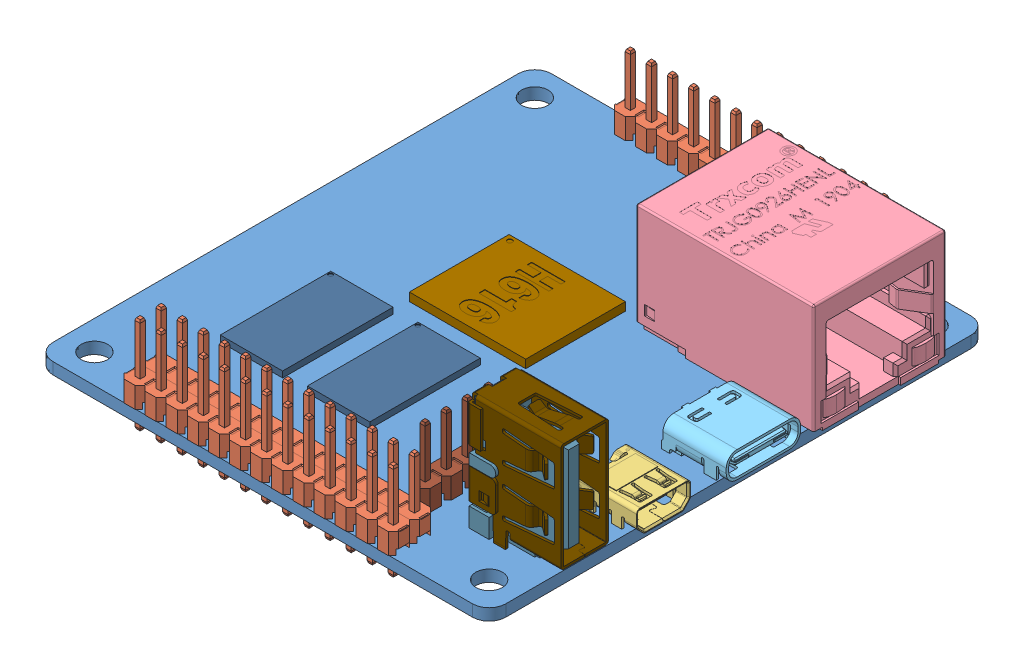
SolidWorks assembly OPiZero2, configuration Default. Lengths in mm.
Overall size (67.58 17.95 60.04).
23 component instances, 18 part files, 26 mates.
Components (placement in the parent):
- pcb_pi-1: pcb_pi [Not Open] [Default] at origin size (67.58 1.4 60)
- PLS-13.step-1: PLS-13.step [Not Open] [Default] at (-15.98 1.4 26.232) x (1 0 0) z (0 1 0) size (33.02 2.54 11.6)
- PLS-13.step-2: PLS-13.step [Not Open] [Default] at (-15.98 1.4 28.772) x (1 0 0) z (0 1 0) size (33.02 2.54 11.6)
- PLS-13.step-3: PLS-13.step [Not Open] [Default] at (-14.48 1.4 -28.73) x (1 0 0) z (0 1 0) size (33.02 2.54 11.6)
- 11.0 Female micro HDMI connector-2: 11.0 Female micro HDMI connector [Not Open] [Domyślna] at (20.75 2.85 10.0003) x (0 0 -1) z (1 0 0) size (6.5 3.51 7.5)
- 12.0 Gigabit ethernet port raspberry-2: 12.0 Gigabit ethernet port raspberry [Not Open] [Default] at (28.25 8.325 -16) x (0 0 -1) z (1 0 0) size (16.1 17.2 21.46)
- 10.0 Female USB connector-3: 10.0 Female USB connector [Not Open] [Domyślna] at (20.64 2.98 -2) x (0 0 -1) z (1 0 0) size (8.94 3.96 8.33)
- Card slot assembly-1: Card slot assembly [Domyślna] at (-30.8948 -12.71 -19.3913) x (0 0 -1) z (0 1 0) size (23.54 11.4 1.48)
  - card slot part 2 metal pin-1: card slot part 2 metal pin [Not Open] [Domyślna] at (-3.5293 -7.6678 12.2938) x (0 -1 0) z (1 0 0) size (7.95 0.89 8.04)
  - sd card slot v1-1: sd card slot v1 [Not Open] [Domyślna] at (-18.1743 -9.7848 12.71) x (-1 0 0) z (0 0 -1) size (23.42 10.28 1.3)
  - part 3 v1-1: part 3 v1 [Not Open] [Domyślna] at (-6.4643 -9.3448 11.38) x (1 0 0) z (0 0 -1) size (11.95 11.4 1.45)
- H616-1: H616 [Not Open] [Default] at (-2.9276 1.52 -3.5752) x (0 0 1) z (-1 0 0) size (12 1.12 14)
- DDR3-1: DDR3 [Not Open] [Default] at (-13.1619 1.7 11.5463) size (7.5 1.03 13.3)
- DDR3-2: DDR3 [Not Open] [Default] at (-2.6086 1.7 11.6068) size (7.5 1.03 13.3)
- PLS-4-1: PLS-4 [Not Open] [Default] at (11.9038 1.4 14.7353) x (0 0 1) z (0 1 0) size (10.16 2.54 11.6)
- RTL-1: RTL [Not Open] [Default] at (2.2806 1.825 -19.9189) size (5 0.85 5)
- 614004184726-1: 614004184726 [Default] at (18.425 9 19.5) x (0 0 -1) z (0 1 0) size (7.12 11 17.04)
  - 614004184726_01-1: 614004184726_01 [Default] at origin size (3.86 8.85 14.75)
  - 614004184726_02-1: 614004184726_02 [Default] at origin size (6.42 10.25 13.85)
  - 614004184726_03-1: 614004184726_03 [Default] at origin size (2.9 8.85 11.95)
  - 614004184726_04-1: 614004184726_04 [Default] at origin size (2.25 8.85 9.95)
  - 614004184726_05-1: 614004184726_05 [Default] at origin size (2.99 8.85 7.45)
  - 614004184726_06-1: 614004184726_06 [Default] at origin size (7.12 11 17.04)
Mates (geometry in assembly coordinates):
- Coincident6: coincident anti-aligned: plane of pcb-1 through (0 1.4 0) normal (0 1 0); plane of PLS-13.step-1 through (-13.44 1.4 26.232) normal (0 -1 0)
- Lock1: lock: unknown of PLS-13.step-1; unknown of PLS-13.step-2
- Parallel5: parallel anti-aligned: line of pcb-1 through (-17.25 1.4 30) axis (0 0 -1); line of PLS-13.step-2 through (-17.25 2.1 28.102) axis (0 0 1)
- Coincident15: coincident: line of pcb-1 through (-17.25 1.4 30) axis (0 0 -1); plane of PLS-13.step-2 through (-17.25 1.4 28.102) normal (-1 0 0)
- Coincident16: coincident anti-aligned: plane of pcb-1 through (0 1.4 0) normal (0 1 0); plane of PLS-13.step-3 through (-11.94 1.4 -28.73) normal (0 -1 0)
- Coincident18: coincident: line of pcb-1 through (-15.75 1.4 -30) axis (0 0 1); plane of PLS-13.step-3 through (-15.75 1.4 -29.4) normal (-1 0 0)
- Coincident19: coincident: line of pcb-1 through (-15.75 1.4 -30) axis (1 0 0); plane of PLS-13.step-3 through (-3.65 1.4 -30) normal (0 0 -1)
- Coincident27: coincident anti-aligned: plane of pcb-1 through (0 1.4 0) normal (0 1 0); plane of 11.0 Female micro HDMI connector-2 through (22.75 1.4 8.1324) normal (0 -1 0)
- Coincident28: coincident: line of pcb-1 through (28.25 1.4 -30) axis (0 0 1); plane of 11.0 Female micro HDMI connector-2 through (28.25 1.85 12.1558) normal (1 0 0)
- Coincident29: coincident anti-aligned: plane of pcb-1 through (0 1.4 0) normal (0 1 0); plane of 12.0 Gigabit ethernet port raspberry-2 through (28.25 1.4 -16) normal (0 -1 0)
- Coincident30: coincident: line of pcb-1 through (28.25 1.4 -30) axis (0 0 1); plane of 12.0 Gigabit ethernet port raspberry-2 through (28.25 8.325 -16) normal (1 0 0)
- Distance6: distance = 0.05 mm: plane of 12.0 Gigabit ethernet port raspberry-2 through (6.9 1.75 -23.95) normal (0 0 -1); line of pcb-1 through (28.25 1.4 -24) axis (-1 0 0)
- Coincident33: coincident anti-aligned: plane of pcb-1 through (0 1.4 0) normal (0 1 0); plane of 10.0 Female USB connector-3 through (28.25 1.4 1.17) normal (0 -1 0)
- Coincident34: coincident: line of pcb-1 through (28.25 1.4 -30) axis (0 0 1); plane of 10.0 Female USB connector-3 through (28.25 3.26 1.17) normal (1 0 0)
- Distance7: distance = 0.47 mm: plane of 10.0 Female USB connector-3 through (28.25 2.7 -6.47) normal (0 0 -1); line of pcb-1 through (28.25 1.4 -6) axis (-1 0 0)
- Coincident40: coincident anti-aligned: plane of pcb-1 through (0 0 0) normal (0 -1 0); plane of Card slot assembly-1/sd card slot v1-1 through (-25.75 0 -7.707) normal (0 1 0)
- Coincident41: coincident aligned: plane of pcb-1 through (-27.25 1.4 30) normal (-1 0 0); plane of Card slot assembly-1/part 3 v1-1 through (-27.25 -1.45 -18.902) normal (-1 0 0)
- Coincident43: coincident anti-aligned: plane of pcb-1 through (0 1.4 0) normal (0 1 0); plane of H616-1 through (-9.4026 1.4 -9.1252) normal (0 -1 0)
- Perpendicular1: perpendicular: plane of pcb-1 through (-27.25 1.4 30) normal (-1 0 0); plane of H616-1 through (-9.9276 2.52 -9.5752) normal (0 0 -1)
- Coincident45: coincident anti-aligned: plane of pcb-1 through (0 1.4 0) normal (0 1 0); circle of DDR3-1
- Coincident46: coincident anti-aligned: plane of pcb-1 through (0 1.4 0) normal (0 1 0); plane of DDR3-2 through (-5.8036 1.4 9.6068) normal (0 -1 0)
- Coincident47: coincident anti-aligned: plane of pcb-1 through (0 1.4 0) normal (0 1 0); plane of PLS-4-1 through (11.9038 1.4 17.2753) normal (0 -1 0)
- Parallel7: parallel anti-aligned: line of pcb-1 through (27.25 1.4 28) axis (0 0 -1); line of PLS-4-1 through (10.6338 1.4 16.6053) axis (0 0 1)
- Coincident48: coincident anti-aligned: plane of pcb_pi-1 through (0 1.4 0) normal (0 1 0); plane of 614004184726-1/614004184726_02-1 through (18.425 1.4 19.5) normal (0 -1 0)
- Coincident49: coincident: line of pcb_pi-1 through (28.25 1.4 -30) axis (0 0 1); plane of 614004184726-1/614004184726_06-1 through (28.25 2.8 19.495) normal (1 0 0)
- Distance8: distance = 0.14 mm: line of pcb_pi-1 through (28.25 1.4 22.5) axis (-1 0 0); plane of 614004184726-1/614004184726_06-1 through (17.95 2.8 22.36) normal (0 0 1)
